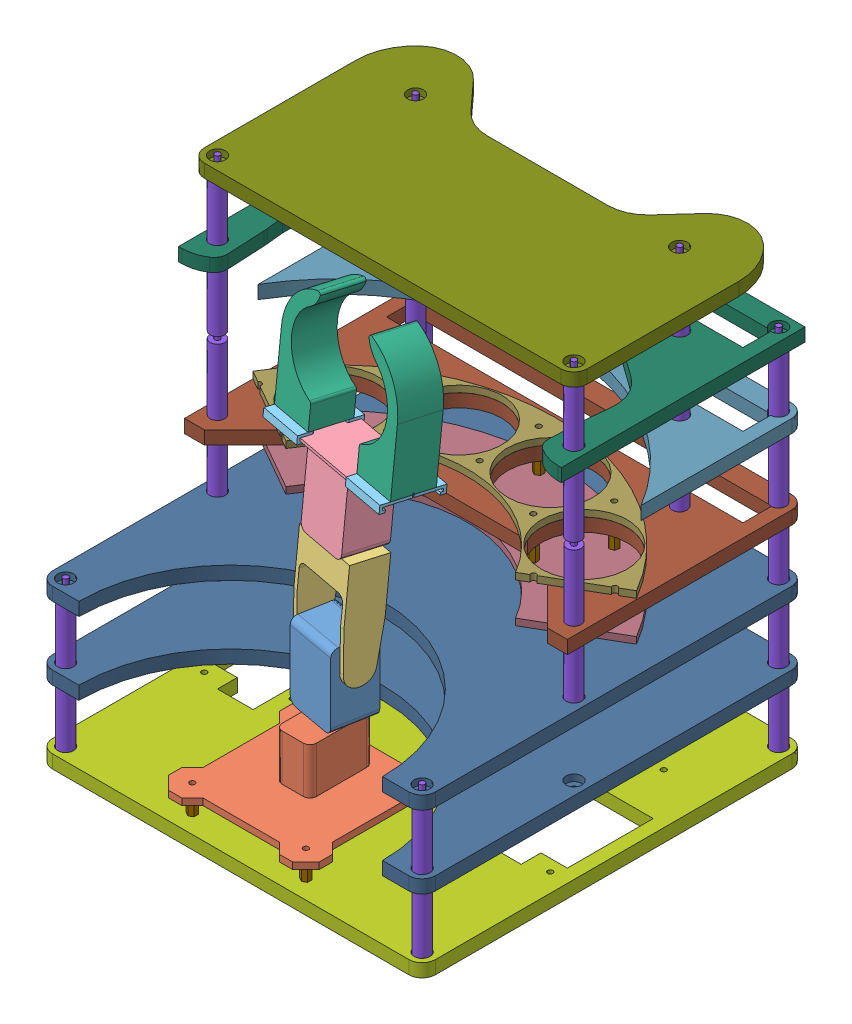
SolidWorks assembly Assemblage, configuration Défaut. Lengths in mm.
Overall size (300.9 341 290).
56 component instances, 16 part files, 103 mates.
Components (placement in the parent):
- Assemblage_bras-1: Assemblage_bras [Défaut] at (-49.1579 56.0755 -15.25) size (120.36 303.09 121.15)
  - Servo2-1: Servo2 [Défaut] at (22.0629 5.137 -51.3648) x (0.176964 0 -0.984217) z (0 -1 0) size (32 38 61)
  - base_phantom-1: base_phantom [Défaut] at (-9.9641 -36.863 15.25) size (114 40 114)
  - junction-1: junction [Défaut] at (69.0565 32.6651 -71.9815) x (-0.984059 0.008265 -0.177648) z (0.17633 -0.084554 -0.980693) size (47 82 27)
  - Servo2 bout-1: Servo2 bout [Défaut] at (23.9286 117.2143 -57.3045) x (0.17633 -0.084554 -0.980693) z (-0.023126 -0.996385 0.081749) size (40 78 63)
  - Pince_bas-1: Pince_bas [Défaut] at (5.448 175.835 -81.9965) x (0.17633 -0.084554 -0.980693) z (0.984059 -0.008265 0.177648) size (44 6 31.62)
  - Pince_bas-2: Pince_bas [Défaut] at (91.7926 175.1098 -66.4091) x (-0.17633 0.084554 0.980693) z (-0.984059 0.008265 -0.177648) size (44 6 31.62)
  - Pince_haut-1: Pince_haut [Défaut] at (28.7549 174.3932 -92.9769) x (0.984059 -0.008265 0.177648) z (-0.17633 0.084554 0.980693) size (31.62 89.36 30)
  - Pince_haut-2: Pince_haut [Défaut] at (68.4857 176.5517 -55.4287) x (-0.984059 0.008265 -0.177648) z (0.17633 -0.084554 -0.980693) size (31.62 89.36 30)
- base-1: base [Défaut] at (-150.5635 -5.7875 0) size (290 10 290)
- support-1: support [Défaut] at (-140.5635 -0.7875 -280) size (11 61 11)
- support-2: support [Défaut] at (129.4365 -0.7875 -280) size (11 61 11)
- support-3: support [Défaut] at (-140.5635 -0.7875 -10) size (11 61 11)
- support-4: support [Défaut] at (129.4365 -0.7875 -10) x (-0.964742 0 0.263197) z (-0.263197 0 -0.964742) size (11 61 11)
- entretoise-1: entretoise [Défaut] at (37.4365 4.2125 -14) x (1 0 0) z (0 1 0) size (6 6.93 15)
- entretoise-2: entretoise [Défaut] at (-48.5635 4.2125 -14) x (1 0 0) z (0 1 0) size (6 6.93 15)
- entretoise-3: entretoise [Défaut] at (37.4365 4.2125 -100) x (1 0 0) z (0 1 0) size (6 6.93 15)
- entretoise-4: entretoise [Défaut] at (-48.5635 4.2125 -100) x (1 0 0) z (0 1 0) size (6 6.93 15)
- Layer1-1-1: Layer1-1 [Défaut] at (-150.5635 59.2125 -290) x (1 0 0) z (0 0 -1) size (290 10 290)
- support-5: support [Défaut] at (129.4365 54.2125 -280) x (0.531822 0 -0.846856) z (0.846856 0 0.531822) size (11 61 11)
- support-6: support [Défaut] at (-140.5635 54.2125 -280) size (11 61 11)
- Layer1-1-2: Layer1-1 [Défaut] at (-150.5635 114.2125 -290) x (1 0 0) z (0 0 -1) size (290 10 290)
- support-7: support [Défaut] at (-140.5635 109.2125 -280) size (11 61 11)
- support-8: support [Défaut] at (129.4365 109.2125 -280) size (11 61 11)
- Layer2-2: Layer2 [Défaut] at (-150.5635 164.2125 -290) x (1 0 0) z (0 0 -1) size (290 10 180)
- support-9: support [Défaut] at (129.4365 54.2125 -10) x (0.570648 0 -0.821195) z (0.821195 0 0.570648) size (11 61 11)
- support-10: support [Défaut] at (-140.5635 54.2125 -10) x (0.763128 0 0.646247) z (-0.646247 0 0.763128) size (11 61 11)
- host-2: host [Défaut] at (-5.5635 169.2125 -79) x (-0.007977 0 -0.999968) z (0 -1 0) size (117.3 289.25 5)
- hostmidlayer-1: hostmidlayer [Défaut] at (-5.5635 134.2125 -79) x (0.127738 0 -0.991808) z (0 1 0) size (128.89 286.78 5)
- entretoise-5: entretoise [Défaut] at (49.0079 154.2125 -174.509) x (0.99332 0 -0.115391) z (0 -1 0) size (6 6.93 15)
- entretoise-6: entretoise [Défaut] at (-83.6659 139.2125 -212.8843) x (1 0 0) z (0 1 0) size (6 6.93 15)
- entretoise-7: entretoise [Défaut] at (-6.0578 139.2125 -188.9989) x (1 0 0) z (0 1 0) size (6 6.93 15)
- entretoise-8: entretoise [Défaut] at (-6.26 139.2125 -233.9984) x (1 0 0) z (0 1 0) size (6 6.93 15)
- entretoise-9: entretoise [Défaut] at (-60.991 154.2125 -174.0147) x (1 0 0) z (0 -1 0) size (6 6.93 15)
- entretoise-10: entretoise [Défaut] at (71.3325 139.2125 -213.5808) x (-0.97745 0 -0.211168) z (0 1 0) size (6 6.93 15)
- support-11: support [Défaut] at (129.4365 109.2125 -125) size (11 61 11)
- support-12: support [Défaut] at (-140.5635 109.2125 -125) size (11 61 11)
- Layer3-1: Layer3 [Défaut] at (-150.5635 224.2125 -290) x (1 0 0) z (0 0 -1) size (290 10 124.19)
- support-13: support [Défaut] at (129.4365 164.2125 -280) x (0.266452 0 0.963848) z (-0.963848 0 0.266452) size (11 61 11)
- support-14: support [Défaut] at (-140.5635 164.2125 -280) x (0.026348 0 0.999653) z (-0.999653 0 0.026348) size (11 61 11)
- support-15: support [Défaut] at (94.4365 164.2125 -240) size (11 61 11)
- support-16: support [Défaut] at (-105.5635 164.2125 -240) x (-0.978949 0 0.204106) z (-0.204106 0 -0.978949) size (11 61 11)
- Layer4-1: Layer4 [Défaut] at (-150.5635 279.2125 -290) x (1 0 0) z (0 0 -1) size (290 10 184.53)
- support-17: support [Défaut] at (-140.5635 219.2125 -280) x (0.729899 0 0.683555) z (-0.683555 0 0.729899) size (11 61 11)
- support-18: support [Défaut] at (94.4365 219.2125 -240) size (11 61 11)
- support-19: support [Défaut] at (-140.5635 164.2125 -125) size (11 61 11)
- support-20: support [Défaut] at (129.4365 219.2125 -280) x (-0.918728 0 0.39489) z (-0.39489 0 -0.918728) size (11 61 11)
- support-21: support [Défaut] at (-140.5635 219.2125 -125) size (11 61 11)
- support-22: support [Défaut] at (-105.5635 219.2125 -240) size (11 61 11)
- Layer5-1: Layer5 [Défaut] at (-150.5635 334.2125 -290) x (1 0 0) z (0 0 -1) size (290 10 166.3)
- support-23: support [Défaut] at (-105.5635 274.2125 -240) x (0.23537 0 -0.971906) z (0.971906 0 0.23537) size (11 61 11)
- support-24: support [Défaut] at (94.4365 274.2125 -240) x (-0.250011 0 0.968243) z (-0.968243 0 -0.250011) size (11 61 11)
- support-25: support [Défaut] at (129.4365 274.2125 -125) size (11 61 11)
- support-26: support [Défaut] at (-140.5635 274.2125 -125) x (0.984829 0 0.173528) z (-0.173528 0 0.984829) size (11 61 11)
- support-27: support [Défaut] at (129.4365 219.2125 -125) x (0.366032 0 -0.930602) z (0.930602 0 0.366032) size (11 61 11)
- support-28: support [Défaut] at (129.4365 164.2125 -125) x (-0.999917 0 0.012862) z (-0.012862 0 -0.999917) size (11 61 11)
Mates (geometry in assembly coordinates):
- Coaxiale1: concentric anti-aligned: cylinder of base-1 through (129.4365 -5.7875 -280) axis (0 1 0) radius 2; cylinder of support-2 through (129.4365 10.2125 -280) axis (0 -1 0) radius 2
- Coïncidente1: coincident anti-aligned: plane of base-1 through (129.4365 -0.7875 -280) normal (0 1 0); plane of support-2 through (129.4365 -0.7875 -280) normal (0 -1 0)
- Coaxiale2: concentric anti-aligned: cylinder of base-1 through (129.4365 -5.7875 -10) axis (0 1 0) radius 2; cylinder of support-4 through (129.4365 10.2125 -10) axis (0 -1 0) radius 2
- Coïncidente2: coincident anti-aligned: plane of base-1 through (129.4365 -0.7875 -10) normal (0 1 0); plane of support-4 through (129.4365 -0.7875 -10) normal (0 -1 0)
- Coaxiale3: concentric anti-aligned: cylinder of base-1 through (-140.5635 -5.7875 -10) axis (0 1 0) radius 2; cylinder of support-3 through (-140.5635 10.2125 -10) axis (0 -1 0) radius 2
- Coïncidente3: coincident anti-aligned: plane of base-1 through (-140.5635 -0.7875 -10) normal (0 1 0); plane of support-3 through (-140.5635 -0.7875 -10) normal (0 -1 0)
- Coaxiale4: concentric anti-aligned: cylinder of base-1 through (-140.5635 -5.7875 -280) axis (0 1 0) radius 2; cylinder of support-1 through (-140.5635 10.2125 -280) axis (0 -1 0) radius 2
- Coïncidente4: coincident anti-aligned: plane of base-1 through (-140.5635 -0.7875 -280) normal (0 1 0); plane of support-1 through (-140.5635 -0.7875 -280) normal (0 -1 0)
- Coaxiale5: concentric aligned: cylinder of Assemblage_bras-1/base_phantom-1 through (-48.5635 19.2125 -14) axis (0 1 0) radius 2; cylinder of entretoise-2 through (-48.5635 14.2125 -14) axis (0 1 0) radius 1.5
- Coaxiale6: concentric aligned: cylinder of Assemblage_bras-1/base_phantom-1 through (37.4365 19.2125 -14) axis (0 1 0) radius 2; cylinder of entretoise-1 through (37.4365 14.2125 -14) axis (0 1 0) radius 1.5
- Coaxiale7: concentric aligned: cylinder of Assemblage_bras-1/base_phantom-1 through (-48.5635 19.2125 -100) axis (0 1 0) radius 2; cylinder of entretoise-4 through (-48.5635 14.2125 -100) axis (0 1 0) radius 1.5
- Coaxiale8: concentric aligned: cylinder of Assemblage_bras-1/base_phantom-1 through (37.4365 19.2125 -100) axis (0 1 0) radius 2; cylinder of entretoise-3 through (37.4365 14.2125 -100) axis (0 1 0) radius 1.5
- Coïncidente5: coincident anti-aligned: plane of Assemblage_bras-1/base_phantom-1 through (-59.122 19.2125 0) normal (0 -1 0); plane of entretoise-2 through (-48.5635 19.2125 -14) normal (0 1 0)
- Coïncidente6: coincident anti-aligned: plane of Assemblage_bras-1/base_phantom-1 through (-59.122 19.2125 0) normal (0 -1 0); plane of entretoise-1 through (37.4365 19.2125 -14) normal (0 1 0)
- Coïncidente7: coincident anti-aligned: plane of Assemblage_bras-1/base_phantom-1 through (-59.122 19.2125 0) normal (0 -1 0); plane of entretoise-3 through (37.4365 19.2125 -100) normal (0 1 0)
- Coïncidente8: coincident anti-aligned: plane of Assemblage_bras-1/base_phantom-1 through (-59.122 19.2125 0) normal (0 -1 0); plane of entretoise-4 through (-48.5635 19.2125 -100) normal (0 1 0)
- Coïncidente9: coincident anti-aligned: plane of base-1 through (-150.5635 4.2125 0) normal (0 1 0); plane of entretoise-2 through (-48.5635 4.2125 -14) normal (0 -1 0)
- Coïncidente10: coincident aligned: plane of Assemblage_bras-1/base_phantom-1 through (-52.5635 24.2125 0) normal (0 0 1); plane of base-1 through (-150.5635 4.2125 0) normal (0 0 1)
- Distance1: distance = 88 mm aligned: plane of Assemblage_bras-1/base_phantom-1 through (51.4365 24.2125 -10) normal (1 0 0); plane of base-1 through (139.4365 4.2125 0) normal (1 0 0)
- Coaxiale12: concentric aligned: cylinder of support-1 through (-140.5635 60.2125 -280) axis (0 -1 0) radius 2; cylinder of Layer1-1-1 through (-140.5635 59.2125 -280) axis (0 -1 0) radius 2
- Coaxiale13: concentric aligned: cylinder of support-2 through (129.4365 60.2125 -280) axis (0 -1 0) radius 2; cylinder of Layer1-1-1 through (129.4365 59.2125 -280) axis (0 -1 0) radius 2
- Coïncidente13: coincident anti-aligned: plane of support-1 through (-140.5635 49.2125 -280) normal (0 1 0); plane of Layer1-1-1 through (-5.5635 49.2125 0) normal (0 -1 0)
- Coaxiale15: concentric aligned: cylinder of support-2 through (129.4365 60.2125 -280) axis (0 -1 0) radius 2; cylinder of support-5 through (129.4365 65.2125 -280) axis (0 -1 0) radius 2
- Coïncidente15: coincident anti-aligned: plane of Layer1-1-1 through (129.4365 54.2125 -280) normal (0 1 0); plane of support-5 through (129.4365 54.2125 -280) normal (0 -1 0)
- Coaxiale16: concentric aligned: cylinder of support-1 through (-140.5635 60.2125 -280) axis (0 -1 0) radius 2; cylinder of support-6 through (-140.5635 65.2125 -280) axis (0 -1 0) radius 2
- Coïncidente16: coincident anti-aligned: plane of Layer1-1-1 through (-140.5635 54.2125 -280) normal (0 1 0); plane of support-6 through (-140.5635 54.2125 -280) normal (0 -1 0)
- Coaxiale19: concentric aligned: cylinder of support-6 through (-140.5635 115.2125 -280) axis (0 -1 0) radius 2; cylinder of Layer1-1-2 through (-140.5635 114.2125 -280) axis (0 -1 0) radius 2
- Coaxiale20: concentric aligned: cylinder of support-3 through (-140.5635 60.2125 -10) axis (0 -1 0) radius 2; cylinder of Layer1-1-2 through (-140.5635 114.2125 -10) axis (0 -1 0) radius 2
- Coaxiale21: concentric aligned: cylinder of support-6 through (-140.5635 115.2125 -280) axis (0 -1 0) radius 2; cylinder of support-7 through (-140.5635 120.2125 -280) axis (0 -1 0) radius 2
- Coïncidente20: coincident anti-aligned: plane of Layer1-1-2 through (-140.5635 109.2125 -280) normal (0 1 0); plane of support-7 through (-140.5635 109.2125 -280) normal (0 -1 0)
- Coaxiale22: concentric aligned: cylinder of support-5 through (129.4365 115.2125 -280) axis (0 -1 0) radius 2; cylinder of support-8 through (129.4365 120.2125 -280) axis (0 -1 0) radius 2
- Coïncidente21: coincident anti-aligned: plane of Layer1-1-2 through (129.4365 109.2125 -280) normal (0 1 0); plane of support-8 through (129.4365 109.2125 -280) normal (0 -1 0)
- Coaxiale23: concentric aligned: cylinder of support-7 through (-140.5635 170.2125 -280) axis (0 -1 0) radius 2; cylinder of Layer2-2 through (-140.5635 164.2125 -280) axis (0 -1 0) radius 2
- Coaxiale24: concentric aligned: cylinder of support-8 through (129.4365 170.2125 -280) axis (0 -1 0) radius 2; cylinder of Layer2-2 through (129.4365 164.2125 -280) axis (0 -1 0) radius 2
- Coaxiale25: concentric aligned: cylinder of support-4 through (129.4365 60.2125 -10) axis (0 -1 0) radius 2; cylinder of support-9 through (129.4365 65.2125 -10) axis (0 -1 0) radius 2
- Coïncidente23: coincident anti-aligned: plane of Layer1-1-1 through (129.4365 54.2125 -10) normal (0 1 0); plane of support-9 through (129.4365 54.2125 -10) normal (0 -1 0)
- Coaxiale26: concentric aligned: cylinder of support-3 through (-140.5635 60.2125 -10) axis (0 -1 0) radius 2; cylinder of support-10 through (-140.5635 65.2125 -10) axis (0 -1 0) radius 2
- Coïncidente24: coincident anti-aligned: plane of Layer1-1-1 through (-140.5635 54.2125 -10) normal (0 1 0); plane of support-10 through (-140.5635 54.2125 -10) normal (0 -1 0)
- Coïncidente25: coincident anti-aligned: plane of Layer2-2 through (-150.5635 164.2125 -290) normal (0 1 0); plane of host-2 through (-5.5635 164.2125 -79) normal (0 -1 0)
- Coaxiale28: concentric aligned: cylinder of Assemblage_bras-1/Servo2-1 through (-5.5635 56.2125 -79) axis (0 1 0) radius 4; cylinder of host-2 through (-5.5635 164.2125 -79) axis (0 1 0) radius 100
- Coaxiale29: concentric anti-aligned: cylinder of host-2 through (-5.5635 164.2125 -79) axis (0 1 0) radius 167; cylinder of hostmidlayer-1 through (-5.5635 139.2125 -79) axis (0 -1 0) radius 167
- Coaxiale30: concentric anti-aligned: cylinder of host-2 through (49.0079 164.2125 -174.509) axis (0 1 0) radius 2; cylinder of entretoise-5 through (49.0079 144.2125 -174.509) axis (0 -1 0) radius 1.5
- Coïncidente27: coincident anti-aligned: plane of Layer2-2 through (-150.5635 154.2125 -290) normal (0 -1 0); plane of entretoise-5 through (49.0079 154.2125 -174.509) normal (0 1 0)
- Coïncidente28: coincident anti-aligned: plane of hostmidlayer-1 through (-5.5635 139.2125 -79) normal (0 1 0); plane of entretoise-5 through (49.0079 139.2125 -174.509) normal (0 -1 0)
- Coaxiale31: concentric anti-aligned: cylinder of hostmidlayer-1 through (49.0079 129.2125 -174.509) axis (0 1 0) radius 2; cylinder of entretoise-5 through (49.0079 144.2125 -174.509) axis (0 -1 0) radius 1.5
- Coaxiale32: concentric anti-aligned: cylinder of hostmidlayer-1 through (71.3325 129.2125 -213.5808) axis (0 1 0) radius 2; cylinder of entretoise-10 through (71.3325 144.2125 -213.5808) axis (0 -1 0) radius 1.5
- Coïncidente29: coincident anti-aligned: plane of hostmidlayer-1 through (-5.5635 139.2125 -79) normal (0 1 0); plane of entretoise-10 through (71.3325 139.2125 -213.5808) normal (0 -1 0)
- Coaxiale38: concentric anti-aligned: cylinder of hostmidlayer-1 through (-83.6659 129.2125 -212.8843) axis (0 1 0) radius 2; cylinder of entretoise-6 through (-83.6659 144.2125 -212.8843) axis (0 -1 0) radius 1.5
- Coaxiale39: concentric anti-aligned: cylinder of host-2 through (-6.26 164.2125 -233.9984) axis (0 1 0) radius 2; cylinder of entretoise-8 through (-6.26 144.2125 -233.9984) axis (0 -1 0) radius 1.5
- Coaxiale40: concentric anti-aligned: cylinder of entretoise-7 through (-6.0578 144.2125 -188.9989) axis (0 -1 0) radius 1.5; cylinder of host-2 through (-6.0578 164.2125 -188.9989) axis (0 1 0) radius 2
- Coïncidente30: coincident anti-aligned: plane of Layer2-2 through (-150.5635 154.2125 -290) normal (0 -1 0); plane of entretoise-8 through (-6.26 154.2125 -233.9984) normal (0 1 0)
- Coïncidente31: coincident anti-aligned: plane of hostmidlayer-1 through (-5.5635 139.2125 -79) normal (0 1 0); plane of entretoise-7 through (-6.0578 139.2125 -188.9989) normal (0 -1 0)
- Coïncidente32: coincident anti-aligned: plane of hostmidlayer-1 through (-5.5635 139.2125 -79) normal (0 1 0); plane of entretoise-6 through (-83.6659 139.2125 -212.8843) normal (0 -1 0)
- Coaxiale41: concentric anti-aligned: cylinder of host-2 through (-60.991 164.2125 -174.0147) axis (0 1 0) radius 2; cylinder of entretoise-9 through (-60.991 144.2125 -174.0147) axis (0 -1 0) radius 1.5
- Coïncidente33: coincident anti-aligned: plane of Layer2-2 through (-150.5635 154.2125 -290) normal (0 -1 0); plane of entretoise-9 through (-60.991 154.2125 -174.0147) normal (0 1 0)
- Coïncidente34: coincident: plane of Layer2-2 through (-150.5635 154.2125 -290) normal (-1 0 0); line of host-2 through (-150.5635 169.2125 -161.8493) axis (0 -1 0)
- Coaxiale42: concentric aligned: cylinder of Layer2-2 through (129.4365 164.2125 -125) axis (0 -1 0) radius 2; cylinder of support-11 through (129.4365 170.2125 -125) axis (0 -1 0) radius 2
- Coaxiale43: concentric aligned: cylinder of Layer2-2 through (-140.5635 164.2125 -125) axis (0 -1 0) radius 2; cylinder of support-12 through (-140.5635 170.2125 -125) axis (0 -1 0) radius 2
- Coaxiale44: concentric aligned: cylinder of support-8 through (129.4365 170.2125 -280) axis (0 -1 0) radius 2; cylinder of Layer3-1 through (129.4365 224.2125 -280) axis (0 -1 0) radius 2
- Coaxiale45: concentric aligned: cylinder of support-7 through (-140.5635 170.2125 -280) axis (0 -1 0) radius 2; cylinder of Layer3-1 through (-140.5635 224.2125 -280) axis (0 -1 0) radius 2
- Coaxiale46: concentric aligned: cylinder of Layer3-1 through (129.4365 224.2125 -280) axis (0 -1 0) radius 2; cylinder of support-13 through (129.4365 225.2125 -280) axis (0 -1 0) radius 2
- Coaxiale47: concentric aligned: cylinder of Layer3-1 through (-140.5635 224.2125 -280) axis (0 -1 0) radius 2; cylinder of support-14 through (-140.5635 225.2125 -280) axis (0 -1 0) radius 2
- Coïncidente37: coincident anti-aligned: plane of Layer2-2 through (-150.5635 164.2125 -290) normal (0 1 0); plane of support-13 through (129.4365 164.2125 -280) normal (0 -1 0)
- Coïncidente38: coincident anti-aligned: plane of Layer3-1 through (-150.5635 214.2125 -290) normal (0 -1 0); plane of support-13 through (129.4365 214.2125 -280) normal (0 1 0)
- Coïncidente39: coincident anti-aligned: plane of Layer3-1 through (-150.5635 214.2125 -290) normal (0 -1 0); plane of support-14 through (-140.5635 214.2125 -280) normal (0 1 0)
- Coaxiale48: concentric aligned: cylinder of Layer3-1 through (94.4365 224.2125 -240) axis (0 -1 0) radius 2; cylinder of support-15 through (94.4365 225.2125 -240) axis (0 -1 0) radius 2
- Coïncidente40: coincident anti-aligned: plane of Layer3-1 through (-150.5635 214.2125 -290) normal (0 -1 0); plane of support-15 through (94.4365 214.2125 -240) normal (0 1 0)
- Coaxiale49: concentric aligned: cylinder of Layer3-1 through (-105.5635 224.2125 -240) axis (0 -1 0) radius 2; cylinder of support-16 through (-105.5635 225.2125 -240) axis (0 -1 0) radius 2
- Coïncidente41: coincident anti-aligned: plane of Layer3-1 through (-150.5635 214.2125 -290) normal (0 -1 0); plane of support-16 through (-105.5635 214.2125 -240) normal (0 1 0)
- Coaxiale50: concentric aligned: cylinder of support-14 through (-140.5635 225.2125 -280) axis (0 -1 0) radius 2; cylinder of support-17 through (-140.5635 280.2125 -280) axis (0 -1 0) radius 2
- Coaxiale51: concentric aligned: cylinder of support-13 through (129.4365 225.2125 -280) axis (0 -1 0) radius 2; cylinder of support-20 through (129.4365 280.2125 -280) axis (0 -1 0) radius 2
- Coaxiale52: concentric aligned: cylinder of support-15 through (94.4365 225.2125 -240) axis (0 -1 0) radius 2; cylinder of support-18 through (94.4365 280.2125 -240) axis (0 -1 0) radius 2
- Coaxiale53: concentric aligned: cylinder of support-16 through (-105.5635 225.2125 -240) axis (0 -1 0) radius 2; cylinder of support-22 through (-105.5635 280.2125 -240) axis (0 -1 0) radius 2
- Coaxiale54: concentric aligned: cylinder of support-19 through (-140.5635 175.2125 -125) axis (0 -1 0) radius 2; cylinder of support-21 through (-140.5635 280.2125 -125) axis (0 -1 0) radius 2
- Distance3: distance = 5 mm anti-aligned: plane of support-19 through (-140.5635 214.2125 -125) normal (0 1 0); plane of support-21 through (-140.5635 219.2125 -125) normal (0 -1 0)
- Coaxiale55: concentric aligned: cylinder of support-12 through (-140.5635 170.2125 -125) axis (0 -1 0) radius 2; cylinder of support-19 through (-140.5635 175.2125 -125) axis (0 -1 0) radius 2
- Coïncidente48: coincident anti-aligned: plane of Layer2-2 through (-150.5635 164.2125 -290) normal (0 1 0); plane of support-19 through (-140.5635 164.2125 -125) normal (0 -1 0)
- Coaxiale56: concentric aligned: cylinder of Layer4-1 through (-140.5635 279.2125 -280) axis (0 -1 0) radius 2; cylinder of support-17 through (-140.5635 280.2125 -280) axis (0 -1 0) radius 2
- Coaxiale57: concentric aligned: cylinder of Layer4-1 through (129.4365 279.2125 -280) axis (0 -1 0) radius 2; cylinder of support-20 through (129.4365 280.2125 -280) axis (0 -1 0) radius 2
- Coaxiale59: concentric aligned: cylinder of support-22 through (-105.5635 280.2125 -240) axis (0 -1 0) radius 2; cylinder of Layer5-1 through (-105.5635 334.2125 -240) axis (0 -1 0) radius 2
- Coaxiale60: concentric aligned: cylinder of support-18 through (94.4365 280.2125 -240) axis (0 -1 0) radius 2; cylinder of Layer5-1 through (94.4365 334.2125 -240) axis (0 -1 0) radius 2
- Coaxiale61: concentric aligned: cylinder of Layer5-1 through (94.4365 334.2125 -240) axis (0 -1 0) radius 2; cylinder of support-24 through (94.4365 335.2125 -240) axis (0 -1 0) radius 2
- Coïncidente51: coincident anti-aligned: plane of Layer5-1 through (-150.5635 324.2125 -290) normal (0 -1 0); plane of support-24 through (94.4365 324.2125 -240) normal (0 1 0)
- Coaxiale62: concentric aligned: cylinder of Layer5-1 through (-105.5635 334.2125 -240) axis (0 -1 0) radius 2; cylinder of support-23 through (-105.5635 335.2125 -240) axis (0 -1 0) radius 2
- Coïncidente53: coincident anti-aligned: plane of Layer5-1 through (-150.5635 324.2125 -290) normal (0 -1 0); plane of support-23 through (-105.5635 324.2125 -240) normal (0 1 0)
- Coïncidente54: coincident aligned: circle of support-27; cylinder of support-28 through (129.4365 225.2125 -125) axis (0 -1 0) radius 2
- Distance2: distance = 5 mm anti-aligned: plane of support-27 through (129.4365 219.2125 -125) normal (0 -1 0); plane of support-28 through (129.4365 214.2125 -125) normal (0 1 0)
- Coaxiale63: concentric anti-aligned: cylinder of Layer4-1 through (129.4365 269.2125 -125) axis (0 1 0) radius 2; cylinder of support-27 through (129.4365 280.2125 -125) axis (0 -1 0) radius 2
- Coïncidente56: coincident anti-aligned: plane of Layer4-1 through (-147.9899 269.2125 -135.47) normal (0 -1 0); plane of support-27 through (129.4365 269.2125 -125) normal (0 1 0)
- Coaxiale65: concentric anti-aligned: cylinder of Layer5-1 through (129.4365 324.2125 -125) axis (0 1 0) radius 2; cylinder of support-25 through (129.4365 335.2125 -125) axis (0 -1 0) radius 2
- Coaxiale66: concentric anti-aligned: cylinder of Layer5-1 through (-140.5635 324.2125 -125) axis (0 1 0) radius 2; cylinder of support-26 through (-140.5635 335.2125 -125) axis (0 -1 0) radius 2
- Coïncidente62: coincident anti-aligned: plane of Layer1-1-2 through (-5.5635 104.2125 0) normal (0 -1 0); plane of support-9 through (129.4365 104.2125 -10) normal (0 1 0)
- Coïncidente72: coincident anti-aligned: plane of support-8 through (129.4365 159.2125 -280) normal (0 1 0); plane of Layer2-2 through (129.4365 159.2125 -280) normal (0 -1 0)
- Coïncidente75: coincident anti-aligned: plane of Layer3-1 through (94.4365 219.2125 -240) normal (0 1 0); plane of support-18 through (94.4365 219.2125 -240) normal (0 -1 0)
- Coïncidente77: coincident anti-aligned: plane of Layer3-1 through (129.4365 219.2125 -280) normal (0 1 0); plane of support-20 through (129.4365 219.2125 -280) normal (0 -1 0)
- Coïncidente79: coincident anti-aligned: plane of Layer2-2 through (129.4365 159.2125 -125) normal (0 -1 0); plane of support-11 through (129.4365 159.2125 -125) normal (0 1 0)
- Coïncidente81: coincident anti-aligned: plane of Layer2-2 through (-140.5635 159.2125 -125) normal (0 -1 0); plane of support-12 through (-140.5635 159.2125 -125) normal (0 1 0)
- Coïncidente83: coincident anti-aligned: plane of Layer4-1 through (-140.5635 274.2125 -125) normal (0 1 0); plane of support-26 through (-140.5635 274.2125 -125) normal (0 -1 0)
- Coïncidente85: coincident anti-aligned: plane of Layer4-1 through (129.4365 274.2125 -125) normal (0 1 0); plane of support-25 through (129.4365 274.2125 -125) normal (0 -1 0)
- Coïncidente87: coincident anti-aligned: plane of Layer4-1 through (94.4365 274.2125 -240) normal (0 1 0); plane of support-24 through (94.4365 274.2125 -240) normal (0 -1 0)
- Coïncidente89: coincident anti-aligned: plane of Layer3-1 through (-140.5635 219.2125 -280) normal (0 1 0); plane of support-17 through (-140.5635 219.2125 -280) normal (0 -1 0)
- Coïncidente91: coincident anti-aligned: plane of Layer4-1 through (-147.9899 269.2125 -135.47) normal (0 -1 0); plane of support-18 through (94.4365 269.2125 -240) normal (0 1 0)
- Coïncidente93: coincident anti-aligned: plane of Layer3-1 through (-105.5635 219.2125 -240) normal (0 1 0); plane of support-22 through (-105.5635 219.2125 -240) normal (0 -1 0)
